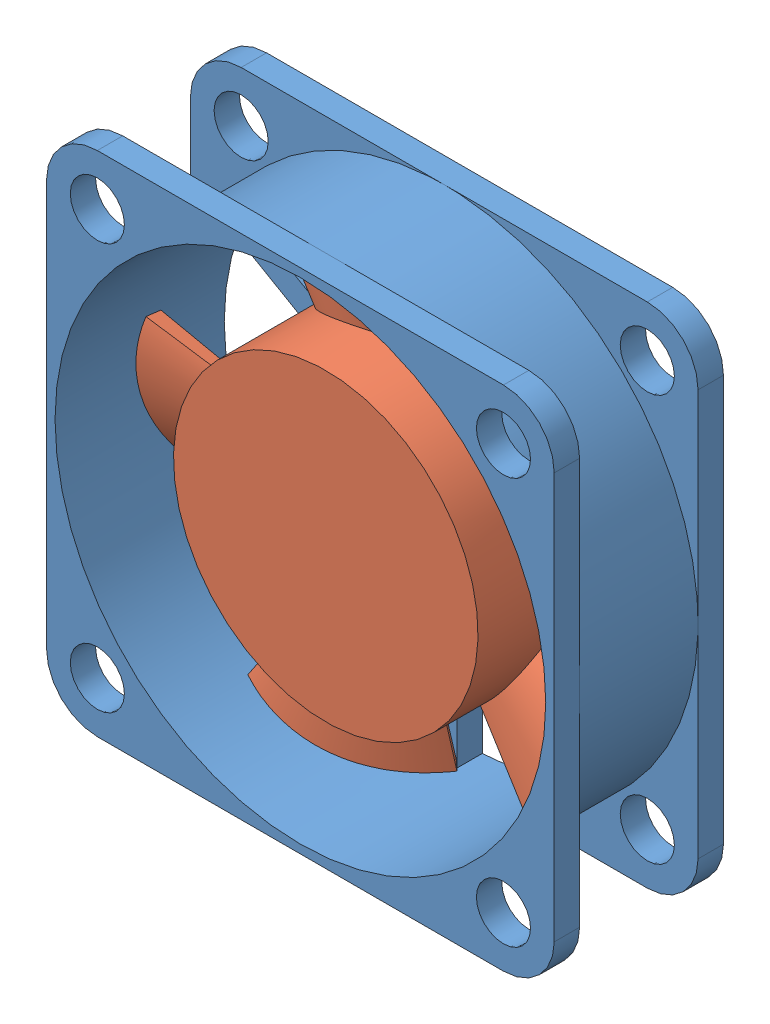
SolidWorks assembly fan, configuration Default. Lengths in mm.
Overall size (39.45 39.46 10).
2 component instances, 2 part files, 2 mates.
Components (placement in the parent):
- fan sub1-1: fan sub1 [Default] at (-0.402 15.9429 23.9537) size (30 30 10)
- fan sub2-1: fan sub2 [Default] at (-0.402 15.9429 33.9537) x (0 0 1) z (-0.65899 0.752151 0) size (8.5 27.91 28)
Mates (geometry in assembly coordinates):
- Coincident1: coincident anti-aligned: circle of fan sub1-1; circle of fan sub2-1
- Perpendicular1: perpendicular: line of fan sub1-1 through (-7.7942 21.0768 25.4537) axis (-0.866025 0.5 0); line of fan sub2-1 through (6.598 28.0672 26.1647) axis (-0.49478 -0.856984 0.144123)
